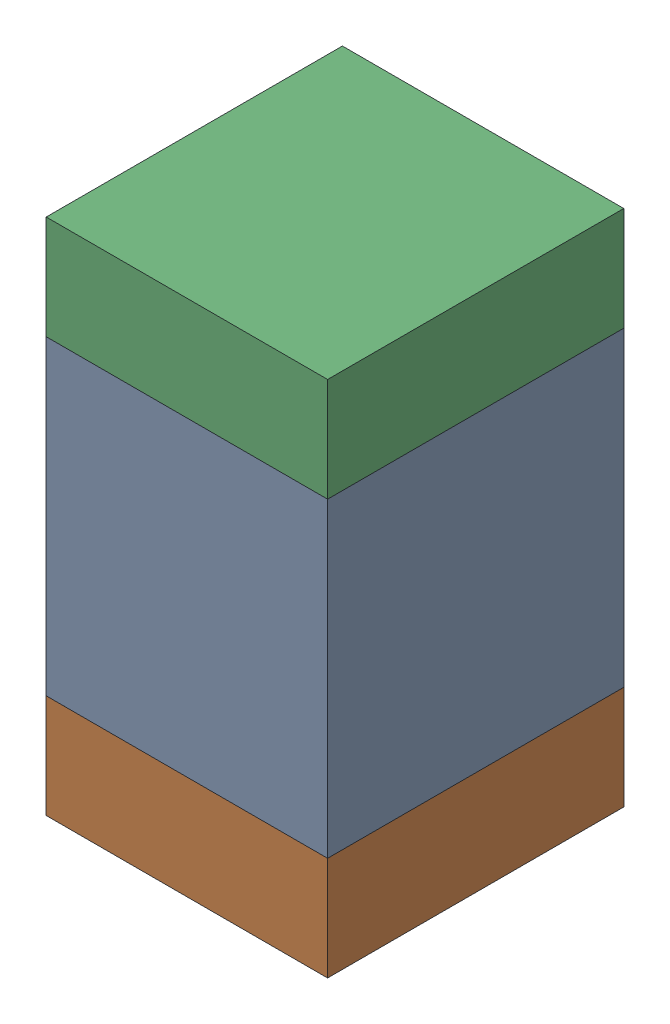
SolidWorks assembly C309_2PCB, configuration Default. Lengths in mm.
Overall size (0.95 1.75 1).
6 component instances, 2 part files, 0 mates.
Components (placement in the parent):
- 761616384-1: 761616384 [Default] at (125.6 93.4 0) size (0.95 1.05 1)
  - Extruded_5-1: Extruded_5 [Default] at origin size (0.95 1.05 1)
- 761616520-1: 761616520 [Default] at (125.6 92.7 0) size (0.95 0.35 1)
  - Extruded_6-1: Extruded_6 [Default] at origin size (0.95 0.35 1)
- 761616520-2: 761616520 [Default] at (125.6 94.1 0) size (0.95 0.35 1)
  - Extruded_6-1: Extruded_6 [Default] at origin size (0.95 0.35 1)
